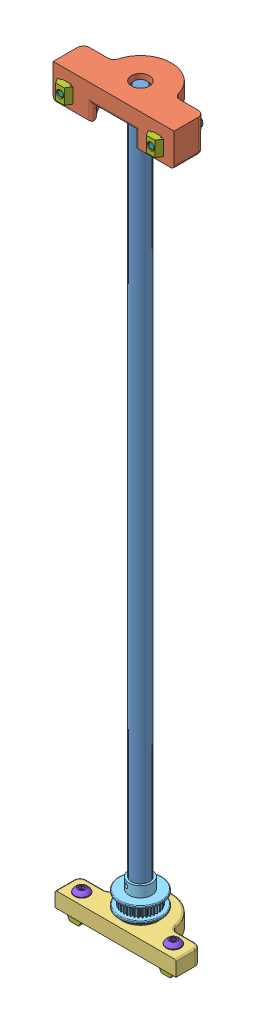
SolidWorks assembly Z_Axis_Module, configuration Default. Lengths in mm.
Overall size (80 491.92 43.77).
14 component instances, 8 part files, 32 mates.
Components (placement in the parent):
- 12mm_Leadscrew-1: 12mm_Leadscrew [Default] at (0 243.6 0) x (0.985154 0 0.171673) z (-0.171673 0 0.985154) size (12 480 12)
- Z_Leadscrew_Bearing_Holder_Top-1: Z_Leadscrew_Bearing_Holder_Top [Default] at (0 485.6 0) x (-1 0 0) z (0 0 1) size (80 22.17 38.27)
- Z_Leadscrew_Bearing_Holder_Base-1: Z_Leadscrew_Bearing_Holder_Base [Default] at origin size (80 10 37)
- 6082Z-8x22x7-1: 6082Z-8x22x7 [6082Z-8x22x7] at (0 480.6 0) x (-0.837169 0 -0.546944) z (0 -1 0) size (22 22 7)
- 6082Z-8x22x7-2: 6082Z-8x22x7 [6082Z-8x22x7] at (0 4 0) x (1 0 0) z (0 1 0) size (22 22 7)
- GT2_Aluminum_Timing_Pulley_36_Tooth-1: GT2_Aluminum_Timing_Pulley_36_Tooth [Default] at (0 29.6 0) x (-0.337691 0 0.941257) z (0.941257 0 0.337691) size (28.13 17.5 28.13)
- 5mmX25mm_Sockethead(McMaster_91290A252)-1: 5mmX25mm_Sockethead(McMaster_91290A252) [91290A252] at (30 474.6 22.7241) size (8.5 8.5 30.5)
- 5mmX25mm_Sockethead(McMaster_91290A252)-2: 5mmX25mm_Sockethead(McMaster_91290A252) [91290A252] at (-30 474.6 22.7241) size (8.5 8.5 30.5)
- HNTTSN5-5-1: HNTTSN5-5 [Default] at (-30 474.6 18.9241) x (0 0 -1) z (0 1 0) size (4.3 10 10)
- HNTTSN5-5-2: HNTTSN5-5 [Default] at (30 474.6 18.9241) x (0 0 -1) z (0 1 0) size (4.3 10 10)
- HNTTSN5-5-3: HNTTSN5-5 [Default] at (-29.9966 -1.2 8.862) x (0 1 0) z (0 0 1) size (4.3 10 10)
- HNTTSN5-5-4: HNTTSN5-5 [Default] at (30 -1.2 8.2271) x (0 1 0) z (0 0 1) size (4.3 10 10)
- 5mmX16mm_Buttonhead(McMaster_91239A232)-1: 5mmX16mm_Buttonhead(McMaster_91239A232) [91239A232] at (30 12.75 8.2271) x (0.745488 0 0.666519) z (0 1 0) size (9.5 9.5 19.24)
- 5mmX16mm_Buttonhead(McMaster_91239A232)-2: 5mmX16mm_Buttonhead(McMaster_91239A232) [91239A232] at (-29.9966 12.75 8.862) x (0.982416 0 0.186707) z (0 1 0) size (9.5 9.5 19.24)
Mates (geometry in assembly coordinates):
- Concentric2: concentric anti-aligned: cylinder of Z_Leadscrew_Bearing_Holder_Top-1 through (0 473.6 0) axis (0 1 0) radius 11.025; cylinder of 6082Z-8x22x7-1 through (0 461.6 0) axis (0 -1 0) radius 11
- Coincident7: coincident anti-aligned: plane of Z_Leadscrew_Bearing_Holder_Top-1 through (0 480.6 0) normal (0 -1 0); plane of 6082Z-8x22x7-1 through (7.5345 480.6 4.9225) normal (0 1 0)
- Concentric3: concentric anti-aligned: cylinder of Z_Leadscrew_Bearing_Holder_Base-1 through (0 10 0) axis (0 -1 0) radius 11.025; cylinder of 6082Z-8x22x7-2 through (0 23 0) axis (0 1 0) radius 11
- Coincident8: coincident anti-aligned: plane of Z_Leadscrew_Bearing_Holder_Base-1 through (0 4 0) normal (0 1 0); plane of 6082Z-8x22x7-2 through (-9 4 0) normal (0 -1 0)
- Concentric4: concentric anti-aligned: cylinder of 12mm_Leadscrew-1 through (0 29.6 0) axis (0 -1 0) radius 4; cylinder of 6082Z-8x22x7-2 through (0 23 0) axis (0 1 0) radius 4
- Concentric5: concentric anti-aligned: cylinder of 12mm_Leadscrew-1 through (0 473.6 0) axis (0 1 0) radius 4; cylinder of 6082Z-8x22x7-1 through (0 461.6 0) axis (0 -1 0) radius 4
- Coincident12: coincident anti-aligned: plane of 12mm_Leadscrew-1 through (0 473.6 0) normal (0 1 0); plane of 6082Z-8x22x7-1 through (3.5998 473.6 2.3519) normal (0 -1 0)
- Distance1: distance = 1.1 mm anti-aligned: plane of GT2_Aluminum_Timing_Pulley_36_Tooth-1 through (0 12.1 0) normal (0 -1 0); plane of 6082Z-8x22x7-2 through (-4.3 11 0) normal (0 1 0)
- Concentric6: concentric anti-aligned: cylinder of 12mm_Leadscrew-1 through (0 29.6 0) axis (0 -1 0) radius 4; cylinder of GT2_Aluminum_Timing_Pulley_36_Tooth-1 through (0 12.1 0) axis (0 1 0) radius 4
- Coincident15: coincident anti-aligned: plane of 12mm_Leadscrew-1 through (0 29.6 0) normal (0 -1 0); plane of GT2_Aluminum_Timing_Pulley_36_Tooth-1 through (0 29.6 0) normal (0 1 0)
- Concentric7: concentric anti-aligned: cylinder of Z_Leadscrew_Bearing_Holder_Base-1 through (-29.9966 10.001 8.862) axis (0 -1 0) radius 2.6; cylinder of 5mmX16mm_Buttonhead(McMaster_91239A232)-2 through (-29.9966 12.75 8.862) axis (0 1 0) radius 4.75
- Coincident16: coincident anti-aligned: plane of Z_Leadscrew_Bearing_Holder_Base-1 through (0 10 0) normal (0 1 0); plane of 5mmX16mm_Buttonhead(McMaster_91239A232)-2 through (-30.8835 10 13.5285) normal (0 -1 0)
- Concentric8: concentric anti-aligned: cylinder of Z_Leadscrew_Bearing_Holder_Base-1 through (30 10.001 8.2271) axis (0 -1 0) radius 2.6; cylinder of 5mmX16mm_Buttonhead(McMaster_91239A232)-1 through (30 12.75 8.2271) axis (0 1 0) radius 4.75
- Coincident17: coincident anti-aligned: plane of Z_Leadscrew_Bearing_Holder_Base-1 through (0 10 0) normal (0 1 0); plane of 5mmX16mm_Buttonhead(McMaster_91239A232)-1 through (26.834 10 11.7681) normal (0 -1 0)
- Concentric9: concentric aligned: cylinder of Z_Leadscrew_Bearing_Holder_Base-1 through (-29.9966 10.001 8.862) axis (0 -1 0) radius 2.6; cylinder of HNTTSN5-5-3 through (-29.9966 -1.2 8.862) axis (0 -1 0) radius 2.067
- Concentric10: concentric aligned: cylinder of Z_Leadscrew_Bearing_Holder_Base-1 through (30 10.001 8.2271) axis (0 -1 0) radius 2.6; cylinder of HNTTSN5-5-4 through (30 -1.2 8.2271) axis (0 -1 0) radius 2.067
- Coincident20: coordinate: point of Z_Leadscrew_Bearing_Holder_Base-1; point of assembly
- Distance2: distance = 0 mm aligned: plane of HNTTSN5-5-3 through (-32.8966 -2 13.862) normal (0 1 0); plane of HNTTSN5-5-4 through (27.1 -2 13.2271) normal (0 1 0)
- Distance3: distance = 2 mm anti-aligned: plane of HNTTSN5-5-3 through (-32.8966 -2 13.862) normal (0 1 0); plane of Z_Leadscrew_Bearing_Holder_Base-1 through (0 0 0) normal (0 -1 0)
- Parallel1: parallel aligned: plane of Z_Leadscrew_Bearing_Holder_Base-1 through (-40 10 16.4541) normal (0 0 1); plane of HNTTSN5-5-3 through (-29.9966 -1.2 13.862) normal (0 0 1)
- Parallel2: parallel aligned: plane of Z_Leadscrew_Bearing_Holder_Base-1 through (-40 10 16.4541) normal (0 0 1); plane of HNTTSN5-5-4 through (30 -1.2 13.2271) normal (0 0 1)
- Concentric11: concentric aligned: line of Z_Leadscrew_Bearing_Holder_Top-1 through (-30 474.6 -5.1598) axis (0 0 1); cylinder of 5mmX25mm_Sockethead(McMaster_91290A252)-2 through (-30 474.6 -7.2759) axis (0 0 1) radius 4.25
- Coincident27: coincident anti-aligned: plane of Z_Leadscrew_Bearing_Holder_Top-1 through (-40 473.6 -2.2759) normal (0 0 -1); plane of 5mmX25mm_Sockethead(McMaster_91290A252)-2 through (-30 474.6 -2.2759) normal (0 0 1)
- Concentric12: concentric aligned: line of Z_Leadscrew_Bearing_Holder_Top-1 through (30 474.6 -4.6541) axis (0 0 1); cylinder of 5mmX25mm_Sockethead(McMaster_91290A252)-1 through (30 474.6 -7.2759) axis (0 0 1) radius 4.25
- Coincident28: coincident anti-aligned: plane of Z_Leadscrew_Bearing_Holder_Top-1 through (40 473.6 -2.2759) normal (0 0 -1); plane of 5mmX25mm_Sockethead(McMaster_91290A252)-1 through (30 474.6 -2.2759) normal (0 0 1)
- Concentric13: concentric aligned: line of Z_Leadscrew_Bearing_Holder_Top-1 through (30 474.6 -4.6541) axis (0 0 1); cylinder of HNTTSN5-5-2 through (30 474.6 18.9241) axis (0 0 1) radius 2.067
- Concentric14: concentric aligned: line of Z_Leadscrew_Bearing_Holder_Top-1 through (-30 474.6 -5.1598) axis (0 0 1); cylinder of HNTTSN5-5-1 through (-30 474.6 18.9241) axis (0 0 1) radius 2.067
- Parallel3: parallel anti-aligned: plane of Z_Leadscrew_Bearing_Holder_Top-1 through (0 485.6 0) normal (0 1 0); plane of HNTTSN5-5-2 through (30 469.6 18.9241) normal (0 -1 0)
- Parallel4: parallel anti-aligned: plane of Z_Leadscrew_Bearing_Holder_Top-1 through (0 485.6 0) normal (0 1 0); plane of HNTTSN5-5-1 through (-30 469.6 18.9241) normal (0 -1 0)
- Distance4: distance = 2 mm anti-aligned: plane of Z_Leadscrew_Bearing_Holder_Top-1 through (40 473.6 17.7241) normal (0 0 1); plane of HNTTSN5-5-2 through (27.1 479.6 19.7241) normal (0 0 -1)
- Distance5: distance = 2 mm anti-aligned: plane of Z_Leadscrew_Bearing_Holder_Top-1 through (40 473.6 17.7241) normal (0 0 1); plane of HNTTSN5-5-1 through (-32.9 479.6 19.7241) normal (0 0 -1)
- Parallel5: parallel aligned: plane of Z_Leadscrew_Bearing_Holder_Top-1 through (40 473.6 17.7241) normal (0 0 1); plane of Z_Leadscrew_Bearing_Holder_Base-1 through (-40 10 16.4541) normal (0 0 1)
